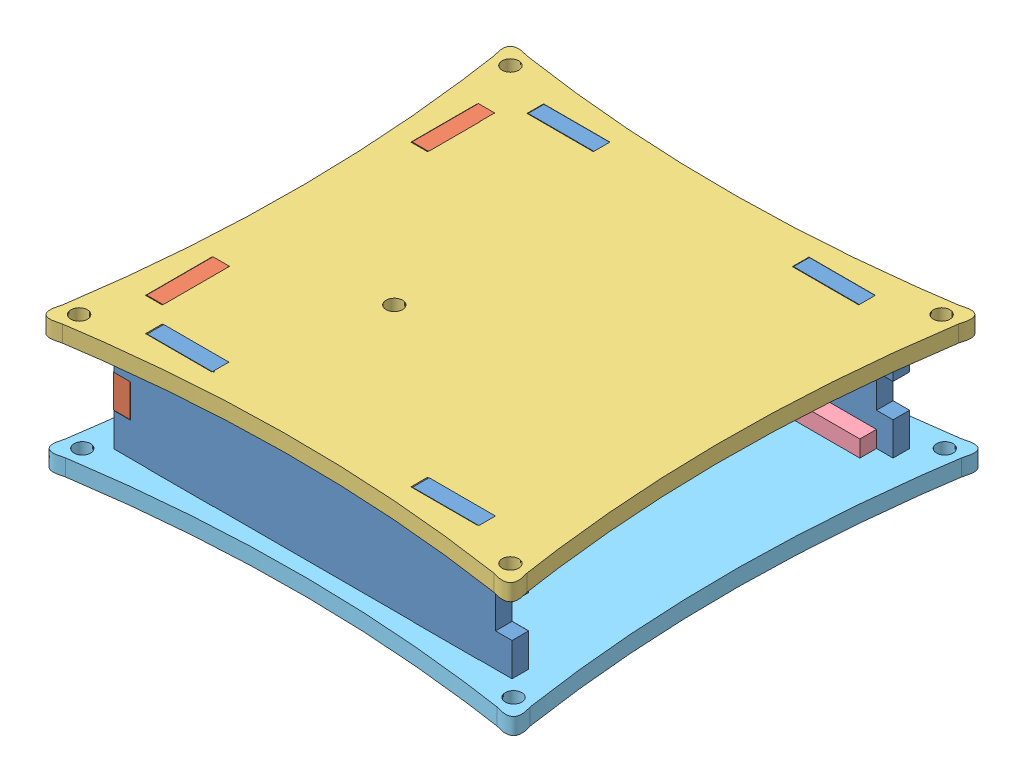
SolidWorks assembly Box Assembly, configuration Default. Lengths in mm.
Overall size (181.42 50.9 181.74).
6 component instances, 5 part files, 9 mates.
Components (placement in the parent):
- Side-1: Side [Default] at (-130.6416 -43.987 38.1808) size (152.4 50.8 6.35)
- Side-2: Side [Default] at (-130.9684 -44.0826 -108.0111) size (152.4 50.8 6.35)
- Back-1: Back [Default] at (-130.9684 -43.987 44.3957) x (0 0 -1) z (1 0 0) size (152.4 50.8 6.35)
- Top-1: Top [Default] at (-143.7911 6.813 57.404) x (0 0 -1) z (0 -1 0) size (180.97 180.97 6.35)
- Runners-1: Runners [Default] at (15.0805 -37.7296 38.0389) x (0 0 -1) z (0 1 0) size (139.7 139.7 6.35)
- Bottom-1: Bottom [Default] at (-143.3416 -44.0796 -121.1562) x (0 0 1) z (0 1 0) size (180.97 180.97 6.35)
Mates (geometry in assembly coordinates):
- Parallel2: parallel anti-aligned: plane of Side-1 through (-130.6416 -43.987 38.1808) normal (0 0 -1); plane of Side-2 through (-130.9684 -44.0826 -101.6611) normal (0 0 1)
- Coincident4: coincident anti-aligned: plane of Side-1 through (-130.6416 -12.237 44.5308) normal (0 -1 0); plane of Back-1 through (-124.6184 -12.237 44.3957) normal (0 1 0)
- Coincident8: coincident anti-aligned: plane of Side-1 through (-130.6416 -24.937 44.5308) normal (0 1 0); plane of Back-1 through (-124.6184 -24.937 44.3957) normal (0 -1 0)
- Coincident9: coincident anti-aligned: plane of Side-2 through (-124.6184 -12.3326 -101.6611) normal (-1 0 0); plane of Back-1 through (-124.6184 -43.987 44.3957) normal (1 0 0)
- Parallel3: parallel aligned: plane of Side-1 through (-124.2916 -12.237 44.5308) normal (-1 0 0); plane of Back-1 through (-130.9684 -43.987 44.3957) normal (-1 0 0)
- Coincident10: coincident anti-aligned: plane of Side-1 through (-92.5416 0.463 44.5308) normal (0 1 0); plane of Top-1 through (34.0089 0.463 57.404) normal (0 -1 0)
- Coincident11: coincident anti-aligned: plane of Side-2 through (-130.9684 -44.0826 -101.6611) normal (0 0 1); plane of Runners-1 through (15.0805 -31.3796 -101.6611) normal (0 0 -1)
- Coincident12: coincident anti-aligned: plane of Side-1 through (-92.5416 -37.637 44.5308) normal (1 0 0); plane of Bottom-1 through (-92.5416 -37.7296 37.5938) normal (-1 0 0)
- Coincident13: coincident anti-aligned: plane of Runners-1 through (15.0805 -37.7296 38.0389) normal (0 -1 0); plane of Bottom-1 through (34.4584 -37.7296 -121.1562) normal (0 1 0)
